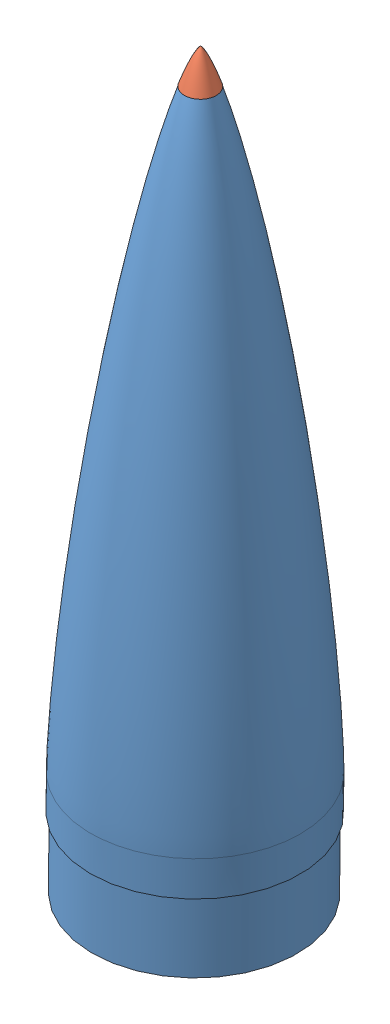
SolidWorks assembly NoseCone, configuration Default. Lengths in mm.
Overall size (313.65 1068.47 304.8).
2 component instances, 2 part files, 2 mates.
Components (placement in the parent):
- NoseCone-1: NoseCone [Default] at (1025.2987 1041.6077 1017.0299) x (-0.008727 -0.999962 0) z (0 0 1) size (1016 304.8 304.8)
- NoseConeTip-2: NoseConeTip [Default] at (1025.2982 1041.5518 1017.0299) x (0.000404 -1 0.000472) z (-0.051616 0.00045 0.998667) size (51.36 45.99 45.99)
Mates (geometry in assembly coordinates):
- Concentric2: concentric aligned: cylinder of NoseCone-1 through (1025.8367 1103.2501 1017.0299) axis (0.008727 0.999962 0) radius 6.35; circle of NoseConeTip-2
- Coincident1: coincident: circle of NoseCone-1; cone of NoseConeTip-2 through (1024.8549 990.7516 1017.0299) axis (-0.008727 -0.999962 0)
